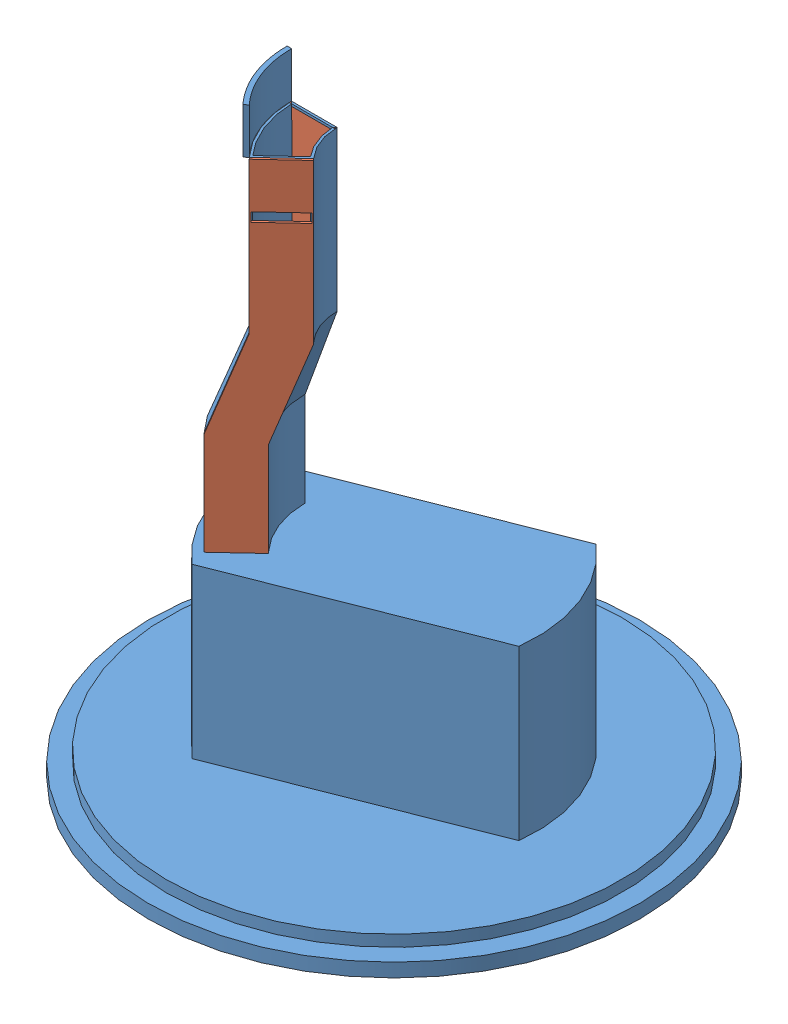
SolidWorks assembly Falling_Full, configuration Default. Lengths in mm.
Overall size (216 255 216).
3 component instances, 2 part files, 4 mates.
Components (placement in the parent):
- Falling_Path-1: Falling_Path [Default] at (30.7706 136.3443 88.9973) size (216 255 216)
- Falling_Path_Plane-1: Falling_Path_Plane [Default] at (5.7706 136.3443 88.9973) size (34.02 150 1)
- Falling_Path_Plane-2: Falling_Path_Plane [Default] at (12.4868 136.3443 106.0472) x (0.731354 0 -0.681998) z (0.681998 0 0.731354) size (34.02 150 1)
Mates (geometry in assembly coordinates):
- Coincident14: coincident: point of Falling_Path-1; point of Falling_Path_Plane-1
- Parallel5: parallel: plane of Falling_Path-1 through (30.7706 136.3443 88.9973) normal (0 0 -1); plane of Falling_Path_Plane-1 through (5.7706 136.3443 89.9973) normal (0 0 1)
- Coincident18: coincident: point of Falling_Path-1; point of Falling_Path_Plane-2
- Coincident21: coincident: plane of Falling_Path-1 through (30.7706 136.3443 88.9973) normal (0.681998 0 0.731354); plane of Falling_Path_Plane-2 through (12.4868 136.3443 106.0472) normal (-0.681998 0 -0.731354)
